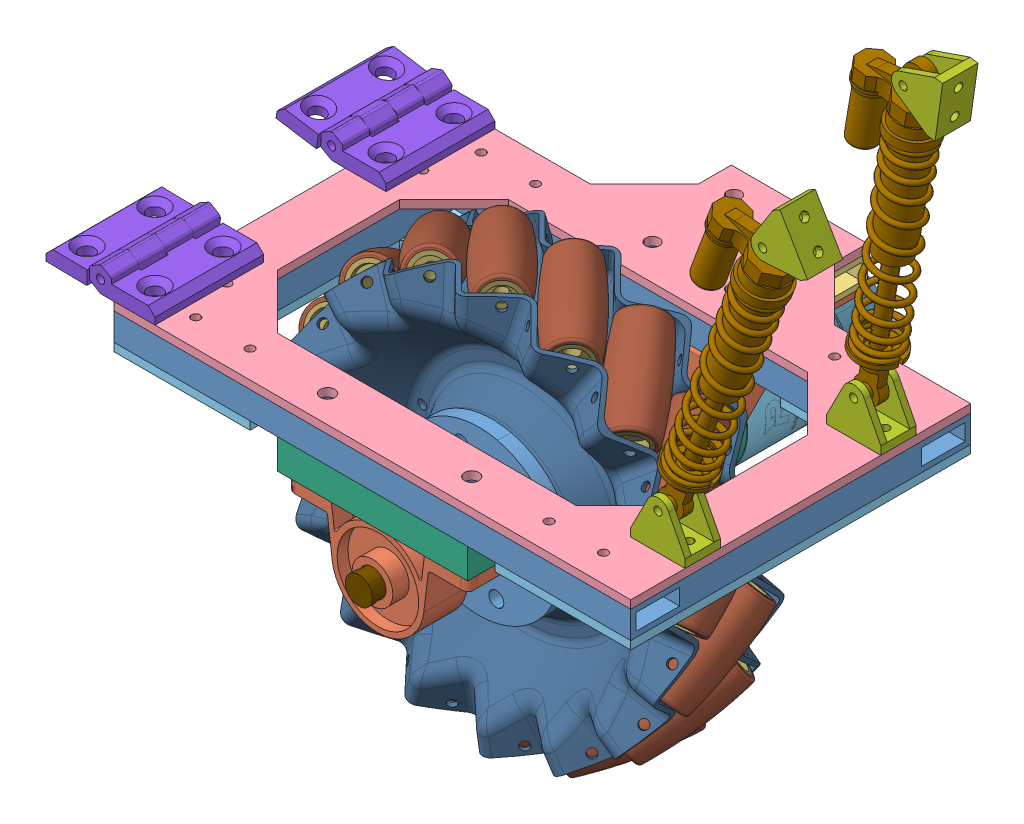
SolidWorks assembly suspension-L, configuration 默认. Lengths in mm.
Overall size (267.27 281 183.1).
105 component instances, 30 part files, 56 mates.
Components (placement in the parent):
- Al_Structure-1: Al_Structure [默认] at (-46.393 -16.6731 0) size (190 10 125)
- 3508_10电机座-1: 3508_10电机座 [Default] at (24.7457 -16.6731 39.834) x (-1 0 0) z (0 0 1) size (50 52 52)
- M3508直流无刷减速电机-1: M3508直流无刷减速电机 [默认] at (-63.9604 -40.3546 -130.941) x (-0.381788 -0.92425 0) z (0 0 1) size (70.45 147.45 98.4)
  - M3508直流无刷减速电机.STEP-1: M3508直流无刷减速电机.STEP [Default] at origin size (81.79 158.79 98.4)
    - 2.STEP-1: 2.STEP [Default] at (-1.7887 18.2683 50.441) x (-0.381788 0.92425 0) z (0.92425 0.381788 0) size (59.4 63.3 59.4)
      - 26.STEP-1: 26.STEP [Default] at (0 27 0) x (-0.381788 0 0.92425) z (-0.92425 0 -0.381788) size (22 6 22)
        - 27.STEP-1: 27.STEP [默认] at origin size (22 6 22)
        - 28.STEP-1: 28.STEP [默认] at (0 2.5 0) size (20 0.2 20)
        - 28.STEP-2: 28.STEP [默认] at (0 -2.7 0) size (20 0.2 20)
      - 26.STEP-2: 26.STEP [Default] at (0 34.5 0) x (-0.381788 0 0.92425) z (-0.92425 0 -0.381788) size (22 6 22)
        - 27.STEP-1: 27.STEP [默认] at origin size (22 6 22)
        - 28.STEP-1: 28.STEP [默认] at (0 2.5 0) size (20 0.2 20)
        - 28.STEP-2: 28.STEP [默认] at (0 -2.7 0) size (20 0.2 20)
      - 23.STEP-1: 23.STEP [默认] at origin size (42.01 26 42)
      - 16.STEP-1: 16.STEP [默认] at (0 31 0) x (-0.707107 0 0.707107) z (0 1 0) size (42 42 14)
      - 25.STEP-1: 25.STEP [默认] at (0 38.5 0) x (0 0 1) z (-1 0 0) size (16.7 1 13.43)
      - 17.STEP-1: 17.STEP [默认] at (0 19.3 0) x (-1 0 0) z (0 0 -1) size (26 44 26)
      - 24.STEP-1: 24.STEP [默认] at (0 37.71 0) x (0 1 0) z (0.381788 0 -0.92425) size (0.42 16 16)
      - 18.STEP-1: 18.STEP [默认] at (12.3744 22 12.3744) x (-0.381788 0 0.92425) z (-0.92425 0 -0.381788) size (5.5 12 5.5)
      - 18.STEP-2: 18.STEP [默认] at (12.3744 22 -12.3744) x (0.92425 0 0.381788) z (-0.381788 0 0.92425) size (5.5 12 5.5)
      - 18.STEP-3: 18.STEP [默认] at (-12.3744 22 -12.3744) x (0.381788 0 -0.92425) z (0.92425 0 0.381788) size (5.5 12 5.5)
      - 18.STEP-4: 18.STEP [默认] at (-12.3744 22 12.3744) x (-0.92425 0 -0.381788) z (0.381788 0 -0.92425) size (5.5 12 5.5)
    - 5.STEP-1: 5.STEP [Default] at (56.824 -105.7062 43.091) x (0.954008 0.299781 0) z (-0.299781 0.954008 0) size (12.31 5.48 111.01)
      - 19.STEP-1: 19.STEP [默认] at origin size (12.31 5.48 13.41)
      - 15.STEP-1: 15.STEP [默认] at (-22.7519 0 22.9937) x (-1 0 0) z (0 0 -1) size (2.5 2.5 100)
      - 15.STEP-2: 15.STEP [默认] at (-18.7519 0 22.9937) x (0 1 0) z (0 0 -1) size (2.5 2.5 100)
      - 15.STEP-3: 15.STEP [默认] at (-14.7519 0 22.9937) x (-1 0 0) z (0 0 -1) size (2.5 2.5 100)
      - 20.STEP-1: 20.STEP [默认] at (-1.9783 -5.4851 11.3276) x (1 0 0) z (0 0 -1) size (11.93 4.93 6.5)
    - 1.STEP-1: 1.STEP [默认] at (-1.7887 18.2683 48.441) x (0.923508 -0.383579 0) z (0 0 1) size (42 42 43.4)
    - 4.STEP-1: 4.STEP [默认] at (-1.7887 18.2683 39.841) x (-0.923508 0.383579 0) z (0.383579 0.923508 0) size (13.16 4.25 21.29)
    - 3.STEP-1: 3.STEP [默认] at (4.5067 -1.7659 43.091) x (0.299781 -0.954008 0) z (0.954008 0.299781 0) size (5.77 4 14.5)
- 3510D孔联轴器-1: 3510D孔联轴器 [Default] at (-128.3393 -63.9318 -10.2) x (0.685829 0.727763 0) z (-0.727763 0.685829 0) size (60 27 60)
- 10mm钢制联轴器-1: 10mm钢制联轴器 [默认] at (-49.6804 -47.7533 1.2992) x (0.685829 0.727763 0) z (0 0 1) size (81.96 81.96 49.1)
  - 10mm钢制联轴器.STEP-1: 10mm钢制联轴器.STEP [Default] at origin size (81.96 81.96 49.1)
    - __________.STEP-1: __________.STEP [Default] at (3.7664 -0.9677 32.1012) size (24 24 44.1)
    - 3510______ ____2.STEP-1: 3510______ ____2.STEP [Default] at (9.8274 82.7684 22.1012) x (0.5 -0.866025 0) z (0.866025 0.5 0) size (60 5 60)
- 轴承座-1: 轴承座 [默认] at (-47.6247 -31.9408 44.5) x (-1 0 0) z (0 0 1) size (67 35 18)
- 电机座垫铝管-1: 电机座垫铝管 [Default] at (24.7457 -16.6731 39.834) x (1 0 0) z (0 1 0) size (50 20 10)
- 玻纤上板-1: 玻纤上板 [Default] at (-46.393 -6.6731 0) x (1 0 0) z (0 1 0) size (190 157 3)
- 玻纤下板-1: 玻纤下板 [Default] at (-46.393 -16.6731 0) x (-1 0 0) z (0 -1 0) size (50 125 3)
- 玻纤下板-2: 玻纤下板 [Default] at (-46.393 -16.6731 0) x (1 0 0) z (0 -1 0) size (50 125 3)
- 3DPrinting垫片-1: 3DPrinting垫片 [Default] at (-46.393 -16.6731 0) x (-1 0 0) z (0 -1 0) size (70 20 11)
- 3mm固定座-1: 3mm固定座 [Default] at (3.2639 -3.6731 11.7194) size (20 17.54 13)
- 3mm固定座-2: 3mm固定座 [Default] at (3.2639 -3.6731 83.7194) size (20 17.54 13)
- 铰链-1: 铰链 [默认] at (-135.002 2.468 -2.5) x (1 0 0) z (0 0 -1) size (40.48 12.73 40) (flexible)
  - 铰链-1: 铰链 [默认] at (-11.391 1.5222 20) size (24 9.08 40)
  - 铰链-2: 铰链 [默认] at (-11.391 1.5222 60) x (-0.987641 -0.156733 0) z (0 0 -1) size (24 9.08 40)
- 铰链-2: 铰链 [默认] at (-135.002 2.468 82.5) x (1 0 0) z (0 0 -1) size (40.07 9.49 40) (flexible)
  - 铰链-1: 铰链 [默认] at (-11.391 1.5222 20) size (24 9.08 40)
  - 铰链-2: 铰链 [默认] at (-11.391 1.5222 60) x (-0.999859 -0.016818 0) z (0 0 -1) size (24 9.08 40)
- 孔距110mm负压避震器.-1: 孔距110mm负压避震器. [默认] at (56.7413 101.2026 -2.4) x (-0.93687 0.349677 0) z (0 0 1) size (30.38 119.45 17)
- 孔距110mm负压避震器.-2: 孔距110mm负压避震器. [默认] at (38.9873 102.9801 -74.4) x (-0.986286 0.165046 0) z (0 0 1) size (30.38 119.45 17)
- 3mm固定座-3: 3mm固定座 [Default] at (106.4134 88.9114 83.7194) x (-0.505514 0.862818 0) z (0 0 1) size (20 17.54 13)
- 3mm固定座-4: 3mm固定座 [Default] at (64.9946 81.264 11.7194) x (0.139688 0.990196 0) z (0 0 1) size (20 17.54 13)
- 麦轮组装右-1: 麦轮组装右 [默认] at (-19.7513 -55.8114 -126.7518) x (0.945939 -0.324344 0) z (0 0 1) size (168 168 48.1)
  - 麦轮钣金-1: 麦轮钣金 [默认] at (-28.4888 0.9465 132.4522) size (142.88 142.88 24.05)
  - 麦轮钣金-3: 麦轮钣金 [默认] at (-28.4888 0.9465 129.2518) x (0.980785 0.19509 0) z (0 0 -1) size (142.88 142.88 24.05)
  - 滚花橡胶轮组装-1: 滚花橡胶轮组装 [默认] at (-11.7664 74.8711 111.2311) x (-0.611613 0.360957 0.704017) z (0.544848 -0.453042 0.705615) size (18.5 18.5 38)
    - 滚花橡胶轮外-1: 滚花橡胶轮外 [默认] at (-9.896 1.7835 38.5971) size (18.5 18.5 38)
    - 滚花铝柱-1: 滚花铝柱 [默认] at (-9.896 1.7835 38) x (0.787441 0.61639 0) z (-0.61639 0.787441 0) size (13 38 13)
  - 滚花橡胶轮组装-2: 滚花橡胶轮组装 [默认] at (27.0215 56.1049 99.7367) x (0.936151 0.121324 -0.330002) z (0.330002 -0.627061 0.705615) size (18.5 18.5 38)
    - 滚花橡胶轮外-1: 滚花橡胶轮外 [默认] at (-9.896 1.7835 38.5971) size (18.5 18.5 38)
    - 滚花铝柱-1: 滚花铝柱 [默认] at (-9.896 1.7835 38) x (0.787441 0.61639 0) z (-0.61639 0.787441 0) size (13 38 13)
  - 滚花橡胶轮组装-3: 滚花橡胶轮组装 [默认] at (40.6784 28.3806 97.7508) x (0.648729 -0.507452 -0.567136) z (0.064917 -0.705615 0.705615) size (18.5 18.5 38)
    - 滚花橡胶轮外-1: 滚花橡胶轮外 [默认] at (-9.896 1.7835 38.5971) size (18.5 18.5 38)
    - 滚花铝柱-1: 滚花铝柱 [默认] at (-9.896 1.7835 38) x (0.787441 0.61639 0) z (-0.61639 0.787441 0) size (13 38 13)
  - 滚花橡胶轮组装-4: 滚花橡胶轮组装 [默认] at (53.3201 5.2227 104.8515) x (0.974131 -0.083344 0.210052) z (-0.210052 -0.676746 0.705615) size (18.5 18.5 38)
    - 滚花橡胶轮外-1: 滚花橡胶轮外 [默认] at (-9.896 1.7835 38.5971) size (18.5 18.5 38)
    - 滚花铝柱-1: 滚花铝柱 [默认] at (-9.896 1.7835 38) x (0.787441 0.61639 0) z (-0.61639 0.787441 0) size (13 38 13)
  - 滚花橡胶轮组装-6: 滚花橡胶轮组装 [默认] at (49.4638 -23.6017 107.4914) x (0.879664 -0.144722 0.453042) z (-0.453042 -0.544848 0.705615) size (18.5 18.5 38)
    - 滚花橡胶轮外-1: 滚花橡胶轮外 [默认] at (-9.896 1.7835 38.5971) size (18.5 18.5 38)
    - 滚花铝柱-1: 滚花铝柱 [默认] at (-9.896 1.7835 38) x (0.787441 0.61639 0) z (-0.61639 0.787441 0) size (13 38 13)
  - 滚花橡胶轮组装-7: 滚花橡胶轮组装 [默认] at (34.7976 -48.3203 109.5966) x (0.769464 -0.121324 0.627061) z (-0.627061 -0.330002 0.705615) size (18.5 18.5 38)
    - 滚花橡胶轮外-1: 滚花橡胶轮外 [默认] at (-9.896 1.7835 38.5971) size (18.5 18.5 38)
    - 滚花铝柱-1: 滚花铝柱 [默认] at (-9.896 1.7835 38) x (0.787441 0.61639 0) z (-0.61639 0.787441 0) size (13 38 13)
  - 滚花橡胶轮组装-8: 滚花橡胶轮组装 [默认] at (11.9043 -65.198 110.9878) x (0.708086 -0.026856 0.705615) z (-0.705615 -0.064917 0.705615) size (18.5 18.5 38)
    - 滚花橡胶轮外-1: 滚花橡胶轮外 [默认] at (-9.896 1.7835 38.5971) size (18.5 18.5 38)
    - 滚花铝柱-1: 滚花铝柱 [默认] at (-9.896 1.7835 38) x (0.787441 0.61639 0) z (-0.61639 0.787441 0) size (13 38 13)
  - 滚花橡胶轮组装-9: 滚花橡胶轮组装 [默认] at (-20.4065 -80.021 108.2514) x (0.291286 -0.803832 0.518658) z (-0.676746 0.210052 0.705615) size (18.5 18.5 38)
    - 滚花橡胶轮外-1: 滚花橡胶轮外 [默认] at (-9.896 1.7835 38.5971) size (18.5 18.5 38)
    - 滚花铝柱-1: 滚花铝柱 [默认] at (-9.896 1.7835 38) x (0.787441 0.61639 0) z (-0.61639 0.787441 0) size (13 38 13)
  - 滚花橡胶轮组装-10: 滚花橡胶轮组装 [默认] at (-46.4094 -74.3284 110.8897) x (0.497758 -0.502453 0.70695) z (-0.544848 0.453042 0.705615) size (18.5 18.5 38)
    - 滚花橡胶轮外-1: 滚花橡胶轮外 [默认] at (-9.896 1.7835 38.5971) size (18.5 18.5 38)
    - 滚花铝柱-1: 滚花铝柱 [默认] at (-9.896 1.7835 38) x (0.787441 0.61639 0) z (-0.61639 0.787441 0) size (13 38 13)
  - 滚花橡胶轮组装-11: 滚花橡胶轮组装 [默认] at (-73.8517 -61.7406 110.8897) x (0.267588 -0.654689 0.70695) z (-0.330002 0.627061 0.705615) size (18.5 18.5 38)
    - 滚花橡胶轮外-1: 滚花橡胶轮外 [默认] at (-9.896 1.7835 38.5971) size (18.5 18.5 38)
    - 滚花铝柱-1: 滚花铝柱 [默认] at (-9.896 1.7835 38) x (0.787441 0.61639 0) z (-0.61639 0.787441 0) size (13 38 13)
  - 滚花橡胶轮组装-12: 滚花橡胶轮组装 [默认] at (-94.388 -39.6091 110.8897) x (-0.00332 -0.707256 0.70695) z (-0.064917 0.705615 0.705615) size (18.5 18.5 38)
    - 滚花橡胶轮外-1: 滚花橡胶轮外 [默认] at (-9.896 1.7835 38.5971) size (18.5 18.5 38)
    - 滚花铝柱-1: 滚花铝柱 [默认] at (-9.896 1.7835 38) x (0.787441 0.61639 0) z (-0.61639 0.787441 0) size (13 38 13)
  - 滚花橡胶轮组装-13: 滚花橡胶轮组装 [默认] at (-104.8916 -11.3035 110.8897) x (-0.273722 -0.652148 0.70695) z (0.210052 0.676746 0.705615) size (18.5 18.5 38)
    - 滚花橡胶轮外-1: 滚花橡胶轮外 [默认] at (-9.896 1.7835 38.5971) size (18.5 18.5 38)
    - 滚花铝柱-1: 滚花铝柱 [默认] at (-9.896 1.7835 38) x (0.787441 0.61639 0) z (-0.61639 0.787441 0) size (13 38 13)
  - 滚花橡胶轮组装-14: 滚花橡胶轮组装 [默认] at (-103.7637 18.8671 110.8897) x (-0.502453 -0.497758 0.70695) z (0.453042 0.544848 0.705615) size (18.5 18.5 38)
    - 滚花橡胶轮外-1: 滚花橡胶轮外 [默认] at (-9.896 1.7835 38.5971) size (18.5 18.5 38)
    - 滚花铝柱-1: 滚花铝柱 [默认] at (-9.896 1.7835 38) x (0.787441 0.61639 0) z (-0.61639 0.787441 0) size (13 38 13)
  - 滚花橡胶轮组装-15: 滚花橡胶轮组装 [默认] at (-91.1758 46.3095 110.8897) x (-0.654689 -0.267588 0.70695) z (0.627061 0.330002 0.705615) size (18.5 18.5 38)
    - 滚花橡胶轮外-1: 滚花橡胶轮外 [默认] at (-9.896 1.7835 38.5971) size (18.5 18.5 38)
    - 滚花铝柱-1: 滚花铝柱 [默认] at (-9.896 1.7835 38) x (0.787441 0.61639 0) z (-0.61639 0.787441 0) size (13 38 13)
  - 滚花橡胶轮组装-16: 滚花橡胶轮组装 [默认] at (-69.0443 66.8457 110.8897) x (-0.707256 0.00332 0.70695) z (0.705615 0.064917 0.705615) size (18.5 18.5 38)
    - 滚花橡胶轮外-1: 滚花橡胶轮外 [默认] at (-9.896 1.7835 38.5971) size (18.5 18.5 38)
    - 滚花铝柱-1: 滚花铝柱 [默认] at (-9.896 1.7835 38) x (0.787441 0.61639 0) z (-0.61639 0.787441 0) size (13 38 13)
  - 滚花橡胶轮组装-17: 滚花橡胶轮组装 [默认] at (-40.7387 77.3494 110.8897) x (-0.652148 0.273722 0.70695) z (0.676746 -0.210052 0.705615) size (18.5 18.5 38)
    - 滚花橡胶轮外-1: 滚花橡胶轮外 [默认] at (-9.896 1.7835 38.5971) size (18.5 18.5 38)
    - 滚花铝柱-1: 滚花铝柱 [默认] at (-9.896 1.7835 38) x (0.787441 0.61639 0) z (-0.61639 0.787441 0) size (13 38 13)
Mates (geometry in assembly coordinates):
- Coincident1: coincident: plane of assembly; plane of assembly; plane of 3508_10电机座-1 through (-68.393 -65.6731 -44.5) normal (0 0 -1); plane of M3508直流无刷减速电机-1/M3508直流无刷减速电机.STEP-1/2.STEP-1/16.STEP-1 through (-55.5854 -36.4836 -44.5) normal (0 0 1)
- Concentric1: concentric: cylinder of assembly; cylinder of assembly; cylinder of 3508_10电机座-1 through (-46.393 -45.6759 -42.5) axis (0 0 -1) radius 13; cylinder of M3508直流无刷减速电机-1/M3508直流无刷减速电机.STEP-1/2.STEP-1/16.STEP-1 through (-46.393 -45.6759 -25.3808) axis (0 0 1) radius 13
- Concentric2: concentric: cylinder of assembly; cylinder of assembly; cylinder of 3508_10电机座-1 through (-46.393 -63.1759 -42.5) axis (0 0 -1) radius 2; cylinder of M3508直流无刷减速电机-1/M3508直流无刷减速电机.STEP-1/2.STEP-1/16.STEP-1 through (-46.393 -63.1759 -44.5) axis (0 0 1) radius 1.65
- Coincident2: coincident: plane of assembly; plane of assembly; plane of Al_Structure-1 through (-46.393 -16.6731 0) normal (0 -1 0); plane of 3508_10电机座-1 through (-68.393 -16.6731 -91.5) normal (0 1 0)
- Coincident3: coincident: plane of assembly; plane of assembly; plane of Al_Structure-1 through (-121.393 -6.6731 -42.5) normal (0 0 1); plane of 3508_10电机座-1 through (-68.393 -65.6731 -42.5) normal (0 0 1)
- Width1: width: plane of assembly; plane of assembly; plane of assembly; plane of assembly; plane of 3508_10电机座-1 through (-71.393 -18.6731 -91.5) normal (-1 0 0); plane of 3508_10电机座-1 through (-21.393 -18.6731 -44.5) normal (1 0 0); plane of Al_Structure-1 through (48.607 -6.6731 62.5) normal (1 0 0); plane of Al_Structure-1 through (-141.393 -6.6731 62.5) normal (-1 0 0)
- Concentric3: concentric: cylinder of M3508直流无刷减速电机-1/M3508直流无刷减速电机.STEP-1/2.STEP-1/17.STEP-1 through (-46.393 -45.6759 -17.2) axis (0 0 1) radius 5; cylinder of 3510D孔联轴器-1 through (-46.393 -45.6759 -17.2) axis (0 0 -1) radius 5.05
- Coincident4: coincident: plane of M3508直流无刷减速电机-1/M3508直流无刷减速电机.STEP-1/2.STEP-1/17.STEP-1 through (-46.393 -45.6759 -37.2) normal (0 0 1); plane of 3510D孔联轴器-1 through (-46.393 -45.6759 -37.2) normal (0 0 -1)
- Concentric8: concentric: cylinder of assembly; cylinder of assembly; cylinder of 10mm钢制联轴器-1/10mm钢制联轴器.STEP-1/__________.STEP-1 through (-46.393 -45.6759 67.5004) axis (0 0 -1) radius 5; cylinder of 轴承座-1 through (-46.393 -45.6759 60.5) axis (0 0 -1) radius 5
- Parallel1: parallel: plane of Al_Structure-1 through (-46.393 -16.6731 0) normal (0 -1 0); plane of 轴承座-1 through (-12.893 -27.6759 60.5) normal (0 1 0)
- Width2: width: plane of 轴承座-1 through (-46.393 -45.6759 60.5) normal (0 0 1); plane of 轴承座-1 through (-46.393 -45.6759 44.5) normal (0 0 -1); plane of Al_Structure-1 through (-121.393 -6.6731 42.5) normal (0 0 -1); plane of Al_Structure-1 through (-141.393 -6.6731 62.5) normal (0 0 1)
- Inplace1: in place: plane of 3508_10电机座-1 through (-68.393 -16.6731 -91.5) normal (0 1 0); plane of ? through (0 -16.6731 0) normal (0 1 0); moOrthogonalPlaneRef_w of 3508_10电机座-1 through (-68.393 -16.6731 -91.5) normal (0 1 0); plane of ? through (0 -16.6731 0) normal (0 0 -1); plane of 3508_10电机座-1 through (-68.393 -16.6731 -91.5) normal (0 1 0); plane of ? through (0 -16.6731 0) normal (1 0 0); plane of 3508_10电机座-1 through (-68.393 -16.6731 -91.5) normal (0 1 0); unknown of 电机座垫铝管-1
- Coincident9: coincident: plane of assembly; plane of assembly; plane of 3508_10电机座-1; plane of 电机座垫铝管-1
- Coincident10: coincident: plane of assembly; plane of assembly; moOrthogonalPlaneRef_w of 3508_10电机座-1 through (24.7457 -16.6731 39.834) normal (0 0 -1); plane of 电机座垫铝管-1 through (24.7457 -16.6731 39.834) normal (0 0 -1)
- Coincident11: coincident: plane of assembly; plane of assembly; moOrthogonalPlaneRef_w of 3508_10电机座-1 through (24.7457 -16.6731 39.834) normal (-1 0 0); plane of 电机座垫铝管-1 through (24.7457 -16.6731 39.834) normal (1 0 0)
- Inplace2: in place: plane of Al_Structure-1 through (-46.393 -6.6731 0) normal (0 1 0); plane of ? through (0 -6.6731 0) normal (0 1 0); plane of Al_Structure-1 through (-46.393 -6.6731 0) normal (0 1 0); plane of ? through (0 -6.6731 0) normal (0 0 -1); plane of Al_Structure-1 through (-46.393 -6.6731 0) normal (0 1 0); plane of ? through (0 -6.6731 0) normal (1 0 0); plane of Al_Structure-1 through (-46.393 -6.6731 0) normal (0 1 0); unknown of 玻纤上板-1
- Coincident12: coincident: plane of assembly through (-46.393 -6.6731 0) normal (0 1 0); plane of assembly through (-46.393 -6.6731 0) normal (0 1 0); plane of Al_Structure-1; plane of 玻纤上板-1
- Coincident13: coincident: plane of assembly; plane of assembly; moOrthogonalPlaneRef_w of Al_Structure-1 through (-46.393 -6.6731 0) normal (0 0 -1); plane of 玻纤上板-1 through (-46.393 -6.6731 0) normal (0 0 -1)
- Coincident14: coincident: plane of assembly; plane of assembly; moOrthogonalPlaneRef_w of Al_Structure-1 through (-46.393 -6.6731 0) normal (-1 0 0); plane of 玻纤上板-1 through (-46.393 -6.6731 0) normal (1 0 0)
- Inplace3: in place: plane of Al_Structure-1 through (-46.393 -16.6731 0) normal (0 -1 0); plane of ? through (0 -16.6731 0) normal (0 -1 0); plane of Al_Structure-1 through (-46.393 -16.6731 0) normal (0 -1 0); plane of ? through (0 -16.6731 0) normal (0 0 -1); plane of Al_Structure-1 through (-46.393 -16.6731 0) normal (0 -1 0); plane of ? through (0 -16.6731 0) normal (-1 0 0); plane of Al_Structure-1 through (-46.393 -16.6731 0) normal (0 -1 0); unknown of ?
- Coincident15: coincident: plane of assembly; plane of assembly; plane of Al_Structure-1; plane of 玻纤下板-1
- Coincident16: coincident: plane of Al_Structure-1 through (-46.393 -16.6731 0) normal (0 0 -1); plane of ? through (-46.393 -16.6731 0) normal (0 0 -1)
- Coincident17: coincident: plane of Al_Structure-1 through (-46.393 -16.6731 0) normal (1 0 0); plane of ? through (-46.393 -16.6731 0) normal (-1 0 0)
- Coincident18: coincident: plane of assembly; plane of assembly; plane of Al_Structure-1 through (-46.393 -16.6731 0) normal (0 -1 0); plane of 玻纤下板-2 through (-46.393 -16.6731 0) normal (0 1 0)
- Coincident19: coincident: plane of assembly; plane of assembly; plane of Al_Structure-1 through (-141.393 -6.6731 -62.5) normal (0 0 -1); plane of 玻纤下板-2 through (-101.393 -19.6731 -62.5) normal (0 0 -1)
- Coincident20: coincident: plane of assembly; plane of assembly; plane of Al_Structure-1 through (-141.393 -6.6731 62.5) normal (-1 0 0); plane of 玻纤下板-2 through (-141.393 -19.6731 62.5) normal (-1 0 0)
- Inplace4: in place: plane of Al_Structure-1 through (-46.393 -16.6731 0) normal (0 -1 0); plane of ? through (0 -16.6731 0) normal (0 -1 0); plane of Al_Structure-1 through (-46.393 -16.6731 0) normal (0 -1 0); plane of ? through (0 -16.6731 0) normal (0 0 -1); plane of Al_Structure-1 through (-46.393 -16.6731 0) normal (0 -1 0); plane of ? through (0 -16.6731 0) normal (-1 0 0); plane of Al_Structure-1 through (-46.393 -16.6731 0) normal (0 -1 0); unknown of ?
- Coincident21: coincident: plane of assembly; plane of assembly; plane of Al_Structure-1; plane of 3DPrinting垫片-1
- Coincident22: coincident: plane of Al_Structure-1 through (-46.393 -16.6731 0) normal (0 0 -1); plane of ? through (-46.393 -16.6731 0) normal (0 0 -1)
- Coincident23: coincident: plane of Al_Structure-1 through (-46.393 -16.6731 0) normal (1 0 0); plane of ? through (-46.393 -16.6731 0) normal (-1 0 0)
- Coincident24: coincident: plane of assembly; plane of assembly; plane of 玻纤上板-1 through (-46.393 -3.6731 0) normal (0 1 0); plane of 3mm固定座-1 through (3.2639 -3.6731 11.7194) normal (0 -1 0)
- Coincident25: coincident: plane of assembly; plane of assembly; plane of 玻纤上板-1 through (48.607 -3.6731 62.5) normal (1 0 0); plane of 3mm固定座-1 through (48.607 -0.6731 -39.5) normal (1 0 0)
- Distance1: distance = 20 mm: plane of assembly; plane of assembly; plane of 3mm固定座-1 through (38.607 9.6269 -42.5) normal (0 0 -1); plane of Al_Structure-1 through (-141.393 -6.6731 -62.5) normal (0 0 -1)
- Coincident26: coincident: plane of assembly; plane of assembly; plane of Al_Structure-1 through (48.607 -6.6731 62.5) normal (1 0 0); plane of 3mm固定座-2 through (48.607 -0.6731 32.5) normal (1 0 0)
- Coincident27: coincident: plane of assembly; plane of assembly; plane of 玻纤上板-1 through (-46.393 -3.6731 0) normal (0 1 0); plane of 3mm固定座-2 through (3.2639 -3.6731 83.7194) normal (0 -1 0)
- Distance2: distance = 20 mm: plane of assembly; plane of assembly; plane of 3mm固定座-2 through (38.607 9.6269 42.5) normal (0 0 1); plane of Al_Structure-1 through (-141.393 -6.6731 62.5) normal (0 0 1)
- Coincident28: coincident: plane of 玻纤上板-1 through (-46.393 -3.6731 0) normal (0 1 0); plane of 铰链-1/铰链-1 through (-146.393 -3.6731 -62.5) normal (0 -1 0)
- Coincident29: coincident: plane of Al_Structure-1 through (-141.393 -6.6731 -62.5) normal (0 0 -1); plane of 铰链-1/铰链-1 through (-146.393 0.9457 -62.5) normal (0 0 -1)
- Coincident30: coincident: plane of 玻纤上板-1 through (-141.393 -3.6731 -62.5) normal (-1 0 0); plane of 铰链-1/铰链-1 through (-141.393 6.3269 -62.5) normal (-1 0 0)
- Coincident31: coincident: plane of 玻纤上板-1 through (-46.393 -3.6731 0) normal (0 1 0); plane of 铰链-2/铰链-1 through (-146.393 -3.6731 22.5) normal (0 -1 0)
- Coincident32: coincident: plane of Al_Structure-1 through (-141.393 -6.6731 62.5) normal (-1 0 0); plane of 铰链-2/铰链-1 through (-141.393 6.3269 22.5) normal (-1 0 0)
- Coincident33: coincident: plane of 玻纤上板-1 through (-141.393 -3.6731 62.5) normal (0 0 1); plane of 铰链-2/铰链-1 through (-146.393 0.9457 62.5) normal (0 0 1)
- Concentric9: concentric: cylinder of assembly; cylinder of assembly; cylinder of 3mm固定座-2 through (38.607 9.6269 42.5) axis (0 0 -1) radius 1.5; cylinder of 孔距110mm负压避震器.-1 through (38.607 9.6269 31) axis (0 0 1) radius 1.5
- Width3: width: plane of 3mm固定座-2 through (38.607 9.6269 42.5) normal (0 0 1); plane of 3mm固定座-2 through (38.607 9.6269 29.5) normal (0 0 -1); plane of 孔距110mm负压避震器.-1 through (38.607 9.6269 34.175) normal (0 0 -1); plane of 孔距110mm负压避震器.-1 through (38.607 9.6269 37.825) normal (0 0 1)
- Concentric10: concentric: cylinder of assembly; cylinder of assembly; cylinder of 3mm固定座-1 through (38.607 9.6269 -29.5) axis (0 0 -1) radius 1.5; cylinder of 孔距110mm负压避震器.-2 through (38.607 9.6269 -41) axis (0 0 1) radius 1.5
- Width4: width: plane of 孔距110mm负压避震器.-2 through (38.607 9.6269 -39.45) normal (0 0 -1); plane of 孔距110mm负压避震器.-2 through (38.607 9.6269 -32.55) normal (0 0 1); plane of 3mm固定座-1 through (38.607 9.6269 -29.5) normal (0 0 1); plane of 3mm固定座-1 through (38.607 9.6269 -42.5) normal (0 0 -1)
- Concentric11: concentric: cylinder of 孔距110mm负压避震器.-1 through (77.0715 112.6827 32.3) axis (0 0 1) radius 1.5; cylinder of 3mm固定座-3 through (77.0715 112.6827 42.5) axis (0 0 -1) radius 1.5
- Width5: width: plane of 孔距110mm负压避震器.-1 through (72.6682 114.3261 38.1) normal (0 0 1); plane of 孔距110mm负压避震器.-1 through (72.6682 114.3261 33.9) normal (0 0 -1); plane of 3mm固定座-3 through (95.5633 101.4959 40.2) normal (0 0 -1); plane of 3mm固定座-3 through (95.5633 101.4959 31.8) normal (0 0 1)
- Concentric12: concentric: cylinder of 孔距110mm负压避震器.-2 through (56.762 118.1184 -39.7) axis (0 0 1) radius 1.5; cylinder of 3mm固定座-4 through (56.762 118.1184 -42.5) axis (0 0 1) radius 1.5
- Width6: width: plane of 3mm固定座-4 through (64.307 97.8659 -40.2) normal (0 0 1); plane of 3mm固定座-4 through (64.307 97.8659 -31.8) normal (0 0 -1); plane of 孔距110mm负压避震器.-2 through (52.1265 118.8941 -38.1) normal (0 0 -1); plane of 孔距110mm负压避震器.-2 through (52.1265 118.8941 -33.9) normal (0 0 1)
- Coincident34: coincident: plane of 10mm钢制联轴器-1/10mm钢制联轴器.STEP-1/3510______ ____2.STEP-1 through (-46.393 -45.6759 18.4004) normal (0 0 -1); plane of 麦轮组装右-1/麦轮钣金-1 through (-46.393 -45.6759 18.4004) normal (0 0 1)
- Coincident35: coincident: plane of 3510D孔联轴器-1 through (-46.393 -45.6759 -10.2) normal (0 0 1); plane of 麦轮组装右-1/麦轮钣金-3 through (-46.393 -45.6759 -10.2) normal (0 0 -1)
- Concentric13: concentric: circle of 10mm钢制联轴器-1/10mm钢制联轴器.STEP-1/3510______ ____2.STEP-1; circle of 麦轮组装右-1/麦轮钣金-1
- Concentric14: concentric: cylinder of 10mm钢制联轴器-1/10mm钢制联轴器.STEP-1/3510______ ____2.STEP-1 through (-61.8241 -62.0506 18.4004) axis (0 0 1) radius 2.75; cylinder of 麦轮组装右-1/麦轮钣金-1 through (-61.8241 -62.0506 18.4004) axis (0 0 1) radius 2.6
- Concentric15: concentric: cylinder of 3510D孔联轴器-1 through (-68.2894 -40.4995 -15.2) axis (0 0 1) radius 2.75; cylinder of 麦轮组装右-1/麦轮钣金-3 through (-68.2894 -40.4995 -10.2) axis (0 0 -1) radius 2.6
- Concentric16: concentric: cylinder of 3510D孔联轴器-1 through (-61.8241 -62.0506 -15.2) axis (0 0 1) radius 2.75; cylinder of 麦轮组装右-1/麦轮钣金-3 through (-61.8241 -62.0506 -10.2) axis (0 0 -1) radius 2.6
